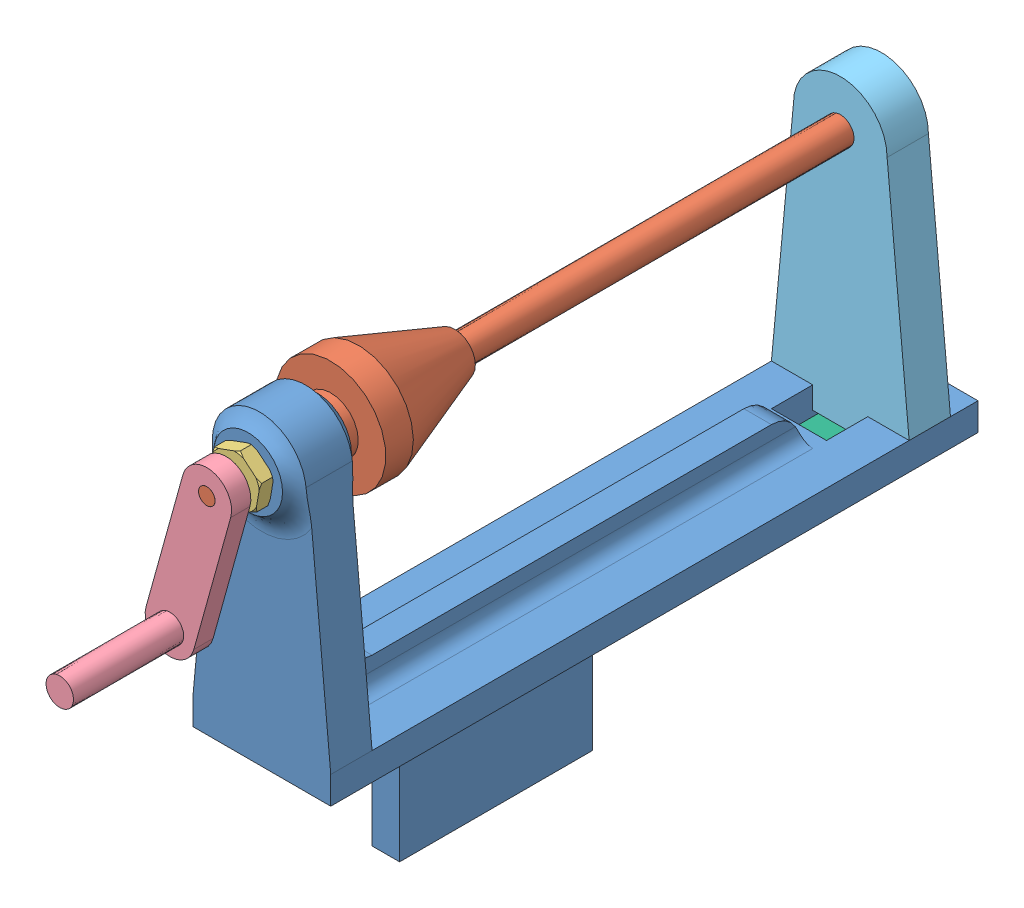
SolidWorks assembly Assem1, configuration Default. Lengths in mm.
Overall size (54.13 172.06 297.5).
7 component instances, 7 part files, 11 mates.
Components (placement in the parent):
- Body-1: Body [Default] at (59.163 103.1222 301.7432) size (50 162 240)
- Spindle-1: Spindle [Default] at (59.163 198.1222 289.2432) x (0 0 1) z (-0.882011 0.471228 0) size (250 40 40)
- Spindle locking nut-1: Spindle locking nut [Default] at (59.163 198.1222 314.2432) x (-0.985225 0.171266 0) z (0.171266 0.985225 0) size (17.32 5 20)
- Spindle handle-1: Spindle handle [Default] at (37.1091 152.355 329.2432) x (0.963518 -0.267643 0) z (0 0 1) size (18 68 47)
- End bearing-2: End bearing [Default] at (49.163 105.1222 99.2432) size (50 110 15)
- Washer-1: Washer [Default] at (59.163 103.1222 91.7432) size (40 5 40)
- Bolt-1: Bolt [Default] at (59.163 92.1222 91.7432) size (12.12 31 14)
Mates (geometry in assembly coordinates):
- Concentric3: concentric anti-aligned: circle of Body-1; circle of Spindle-1
- Coincident2: coincident anti-aligned: plane of Body-1 through (59.163 198.1222 289.2432) normal (0 0 -1); plane of Spindle-1 through (59.163 198.1222 289.2432) normal (0 0 1)
- Concentric4: concentric anti-aligned: circle of Spindle-1; circle of Spindle locking nut-1
- Coincident3: coincident anti-aligned: plane of Body-1 through (59.163 198.1222 314.2432) normal (0 0 1); plane of Spindle locking nut-1 through (59.163 198.1222 314.2432) normal (0 0 -1)
- Coincident4: coincident anti-aligned: circle of Spindle-1; circle of Spindle handle-1
- Coincident16: coincident anti-aligned: cylinder of Spindle-1 through (59.163 198.1222 88.8917) axis (0 0 -1) radius 4; circle of End bearing-2
- Coincident17: coincident anti-aligned: plane of Spindle-1 through (59.163 198.1222 99.2432) normal (0 0 -1); plane of End bearing-2 through (59.163 198.1222 99.2432) normal (0 0 1)
- Concentric5: concentric anti-aligned: circle of End bearing-2; circle of Washer-1
- Coincident18: coincident anti-aligned: plane of Body-1 through (59.163 103.1222 309.2432) normal (0 -1 0); plane of Washer-1 through (59.163 103.1222 91.7432) normal (0 1 0)
- Concentric6: concentric: circle of Washer-1; cylinder of Bolt-1 through (59.163 123.1222 91.7432) axis (0 -1 0) radius 4
- Coincident19: coincident anti-aligned: plane of Washer-1 through (59.163 98.1222 91.7432) normal (0 -1 0); plane of Bolt-1 through (59.163 98.1222 91.7432) normal (0 1 0)
